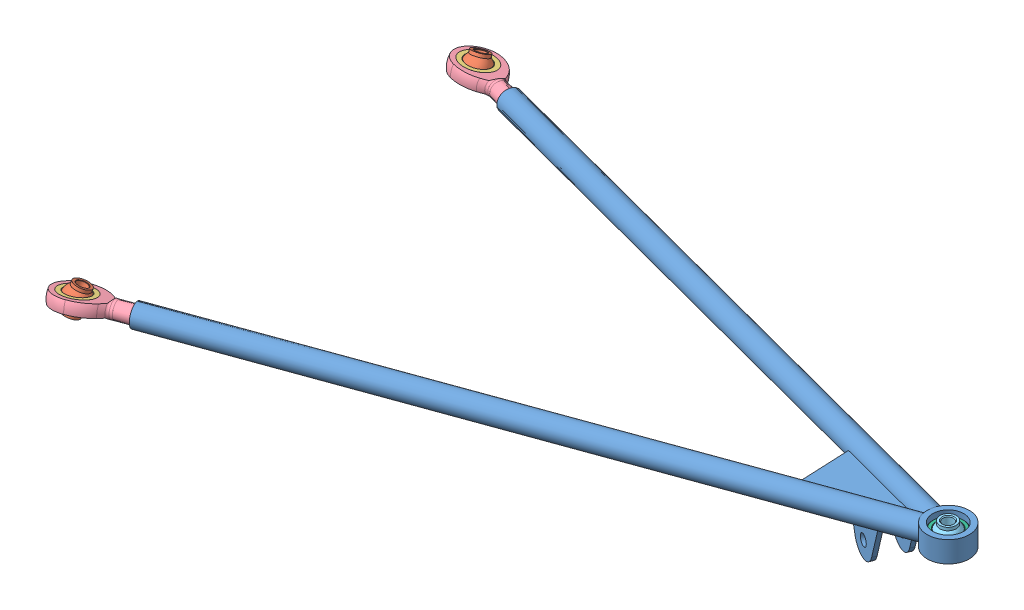
SolidWorks assembly Rear Top Wishbone, configuration Default. Lengths in mm.
Overall size (418.15 65.29 303.68).
12 component instances, 6 part files, 6 mates.
Components (placement in the parent):
- Rear Top Wishbone-1: Rear Top Wishbone [Default<As Machined>] at (264.3052 252.1611 484.6777) size (374.53 35.42 236.87)
- HXAM-4T Rod End-1: HXAM-4T Rod End [Default] at (-121.5011 252.1611 624.3775) x (0.897746 0.034217 0.439183) z (-0.419021 0.373943 0.827398) size (66.97 41.09 66.63) (flexible)
  - HXAM-4T Ball-1: HXAM-4T Ball [Default] at (0 0 -49.2252) size (15.06 15.06 15.06)
  - HXAM-4T Sleeve-1: HXAM-4T Sleeve [Default] at (34.1911 12.1575 -33.2609) x (-0.70005 0.015607 -0.713924) z (-0.694585 -0.246976 0.675688) size (19.53 6.73 19.53)
  - HXAM-4T Housing-1: HXAM-4T Housing [Default] at (34.1911 12.1575 -33.2609) x (-0.70005 0.015607 -0.713924) z (-0.694585 -0.246976 0.675688) size (27.48 26.04 62.51)
- HXAM-4T Rod End-2: HXAM-4T Rod End [Default] at (-121.5011 252.1611 383.0775) x (0.980034 0.019564 -0.197864) z (0.169188 0.440687 0.881572) size (70.84 43.06 55.13) (flexible)
  - HXAM-4T Ball-1: HXAM-4T Ball [Default] at (0 0 -49.2252) size (15.06 15.06 15.06)
  - HXAM-4T Sleeve-1: HXAM-4T Sleeve [Default] at (44.1714 -10.3443 19.105) x (-0.425465 -0.178049 0.887287) z (-0.897334 0.210143 -0.388113) size (19.53 6.73 19.53)
  - HXAM-4T Housing-1: HXAM-4T Housing [Default] at (44.1714 -10.3443 19.105) x (-0.425465 -0.178049 0.887287) z (-0.897334 0.210143 -0.388113) size (27.48 26.04 62.51)
- HAB-4T Bearing-1: HAB-4T Bearing [Default] at (264.3052 252.1611 484.6777) x (0.999975 -0.007095 -0.000077) z (-0.000077 -0.021669 0.999765) size (19.45 15.06 19.55) (flexible)
  - HAB-4T Ball-1: HAB-4T Ball [Default] at origin size (15.06 15.06 15.06)
  - HAB-4T Cup-1: HAB-4T Cup [Default] x (0.999428 0.006373 -0.033204) z (0.033057 0.021893 0.999214) size (18.8 6.48 18.8)
Mates (geometry in assembly coordinates):
- Concentric1: concentric anti-aligned: cylinder of Rear Top Wishbone-1 through (264.3052 258.9388 484.6777) axis (0 -1 0) radius 9.3345; cylinder of HAB-4T Bearing-1/HAB-4T Cup-1 through (264.3052 252.1611 484.6777) axis (0 1 0) radius 9.398
- Coincident1: coincident anti-aligned: plane of Rear Top Wishbone-1 through (264.3052 248.9226 484.6777) normal (0 1 0); plane of HAB-4T Bearing-1/HAB-4T Cup-1 through (264.3052 248.9226 484.6777) normal (0 -1 0)
- Concentric2: concentric anti-aligned: cylinder of Rear Top Wishbone-1 through (264.3052 252.1611 484.6777) axis (-0.940257 0 0.340465) radius 6.35; cylinder of HXAM-4T Rod End-1/HXAM-4T Housing-1 through (-89.6883 252.1611 612.8582) axis (0.940257 0 -0.340465) radius 4.7625
- Concentric3: concentric aligned: cylinder of Rear Top Wishbone-1 through (-94.6173 252.1611 390.1572) axis (0.96703 0 0.254663) radius 6.35; cylinder of ? through (-88.7825 252.1611 391.6938) axis (0.96703 0 0.254663) radius 4.7625
- Coincident2: coincident: point of Rear Top Wishbone-1; point of HXAM-4T Rod End-2/HXAM-4T Ball-1
- Coincident3: coincident: point of Rear Top Wishbone-1; point of HXAM-4T Rod End-1/HXAM-4T Ball-1
